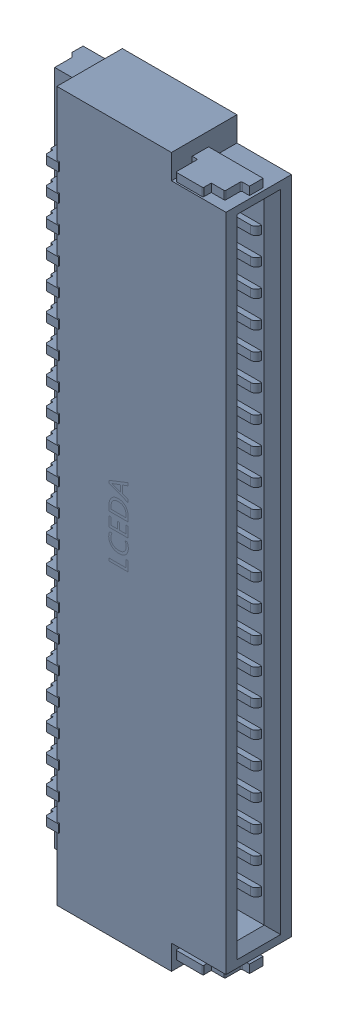
SolidWorks assembly FPC1, configuration Défaut. Lengths in mm.
Overall size (3.8 13 1.23).
4 component instances, 1 part files, 0 mates.
Components (placement in the parent):
- FH34SRJ-22S-0.5SH(50)-1: FH34SRJ-22S-0.5SH(50) [Défaut] at (70.7642 -1.4741 -0.4818) x (0 -1 0) z (0 0 -1) size (13 3.8 1.23)
  - FPC1.step_745-1: FPC1.step_745 [Défaut] at (8.84 -9.4501 1.6001) size (13 3.8 1.23)
    - FFC-SMD_22P-P0.50_HRS_FH34SRJ-22S-0.5SH.step-1: FFC-SMD_22P-P0.50_HRS_FH34SRJ-22S-0.5SH.step [Défaut] at origin size (13 3.8 1.23)
      - SOLID.step_747-1: SOLID.step_747 [Défaut] at origin size (13 3.8 1.23)
